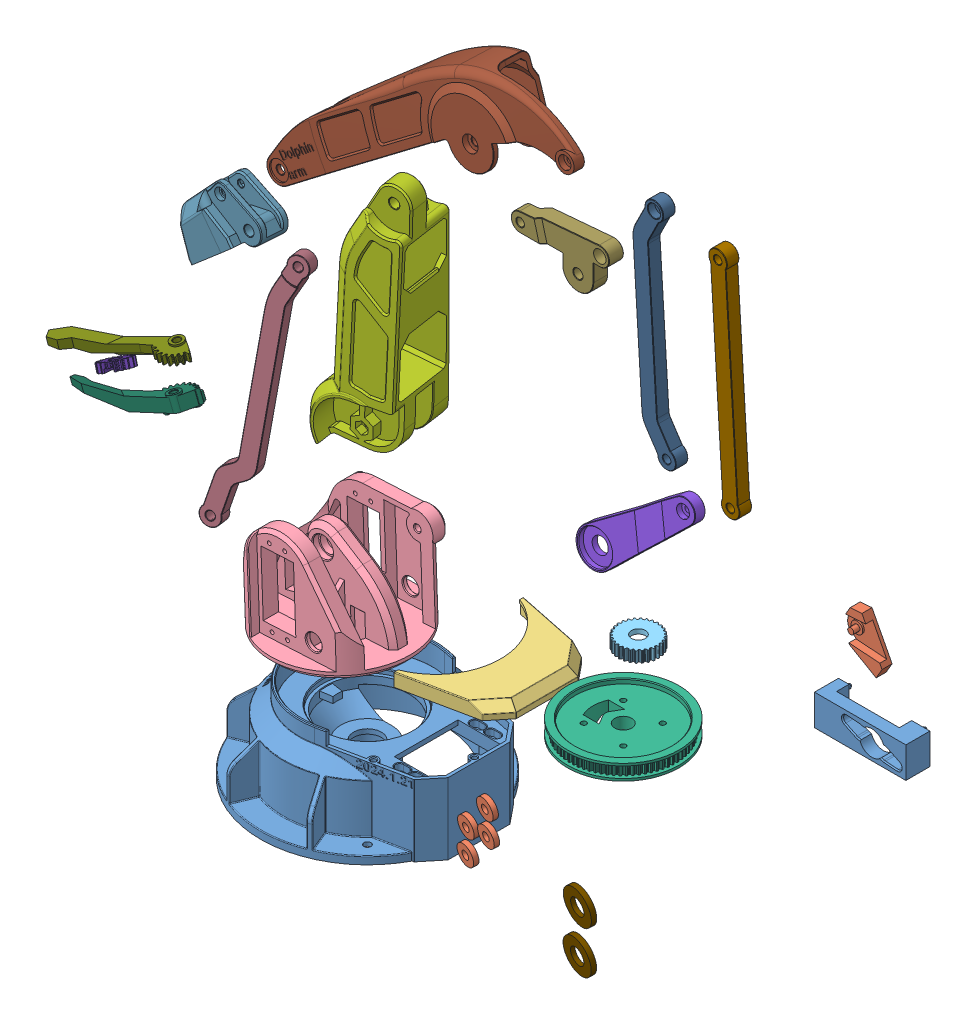
SolidWorks assembly 3D打印件, configuration 默认. Lengths in mm.
Overall size (410.43 477.39 187.89).
24 component instances, 20 part files, 0 mates.
Components (placement in the parent):
- 固定底座-1: 固定底座 [默认] at (8.5901 -52.2812 141) size (141 54.5 138)
- B轴轴承压块-1: B轴轴承压块 [默认] at (107.7408 -28.0802 176.9772) x (0.169291 0.12163 -0.978032) z (0.985197 0.006288 0.171313) size (3 13 13)
- B轴轴承压块-2: B轴轴承压块 [默认] at (108.8742 -7.5286 165.5563) x (0.169291 0.12163 -0.978032) z (0.985197 0.006288 0.171313) size (3 13 13)
- B轴轴承压块-3: B轴轴承压块 [默认] at (115.5882 -16.5606 171.5063) x (0.169291 0.12163 -0.978032) z (0.985197 0.006288 0.171313) size (3 13 13)
- B轴轴承压块-4: B轴轴承压块 [默认] at (100.9885 -19.429 169.8681) x (0.169291 0.12163 -0.978032) z (0.985197 0.006288 0.171313) size (3 13 13)
- 固定底座盖子-1: 固定底座盖子 [默认] at (15.5261 11.5755 103.9088) x (1 0 0) z (0 1 0) size (57 83.65 8.5)
- （15课程结束时保存）（答案）旋转底座-1: （15课程结束时保存）（答案）旋转底座 [默认] at (-1.094 29.7626 147.8189) x (0.999059 0.042643 -0.007925) z (0.007686 0.005763 0.999954) size (95.84 68.65 88)
- HTPA28S3M060_A_H5_b-1: HTPA28S3M060_A_H5_b [默认] at (113.9919 47.7205 71.4501) x (0 -1 0) z (0.989778 0 -0.142614) size (7 25.87 25.87)
- HTPA72S3M060_A_H8_b-1: HTPA72S3M060_A_H8_b [默认] at (129.6039 9.1182 96.8713) x (0 1 0) z (0 0 -1) size (17.1 72 72)
- （15课程结束时保存）（答案）BC连杆-1: （15课程结束时保存）（答案）BC连杆 [默认] at (19.9737 124.142 118.0568) x (0.989919 -0.035409 -0.13714) z (0.136704 -0.014475 0.990506) size (142.89 159.27 45.2)
- （15课程结束时保存）（答案）C轴摇杆-1: （15课程结束时保存）（答案）C轴摇杆 [默认] at (67.5776 61.1657 46.3873) x (0.764092 0.637365 -0.099645) z (0.037421 0.110413 0.993181) size (79.5 24 12.2)
- C轴连杆-1: C轴连杆 [默认] at (141.8774 114.4852 40.0649) x (-0.998176 -0.060372 0) z (0 0 -1) size (12 147 8)
- 下水平连杆-1: 下水平连杆 [默认] at (94.248 114.7266 33.5587) x (-0.998176 -0.060372 0) z (0 0 -1) size (21 147 8)
- CD连杆-1: CD连杆 [默认] at (65.2389 324.7816 113.0597) x (0.899876 0.435011 -0.031431) z (0.010739 0.049943 0.998694) size (217.38 87.46 37)
- 三角形连杆-1: 三角形连杆 [默认] at (135.055 287.8892 131.6249) x (-1 0 0) z (0 0 -1) size (60.91 32.85 12)
- 上水平连杆-1: 上水平连杆 [默认] at (-43.1976 204.4505 129.5236) x (0.194201 0.958435 -0.209019) z (0.268385 0.153034 0.951078) size (157 23.5 10.5)
- 夹爪支架-1: 夹爪支架 [默认] at (-64.0955 218.394 135.9651) x (0.757628 0.650575 -0.052449) z (0.006621 0.072694 0.997332) size (60.52 34.67 30)
- 上手指齿轮组合-4: 上手指齿轮组合 [默认] at (-56.7499 154.141 175.8149) x (0.922109 0.342992 0.179087) z (-0.160943 -0.080909 0.983642) size (65.48 17.8 37.01)
- 下手指齿轮组合-4: 下手指齿轮组合 [默认] at (-75.0796 156.157 163.0303) x (0.905931 0.17816 -0.384121) z (0.400897 -0.068928 0.913526) size (69.3 14.8 16)
- 主动齿-2: 主动齿 [M1X17] at (-107.8173 140.2919 186.0806) x (0.61814 0.488953 0.61549) z (-0.473081 0.856723 -0.205475) size (18.97 18.89 5)
- A轴轴承压块-1: A轴轴承压块 [默认] at (174.0065 -54.3953 171.034) x (0.169291 0.12163 -0.978032) z (0.985197 0.006288 0.171313) size (3 22 22)
- A轴轴承压块-2: A轴轴承压块 [默认] at (174.5478 -26.3918 171.4662) x (0.169291 0.12163 -0.978032) z (0.985197 0.006288 0.171313) size (3 22 22)
- (29课最后保存）（答案）19-B轴舵机舵盘定位块-1: (29课最后保存）（答案）19-B轴舵机舵盘定位块 [默认] at (246.0493 41.4499 25.9149) size (59 19.9 20.5)
- (29课最后保存）（答案）20-C轴舵机舵盘定位块-1: (29课最后保存）（答案）20-C轴舵机舵盘定位块 [默认] at (285.6963 90.7263 48.1149) size (26.71 31.47 7)
